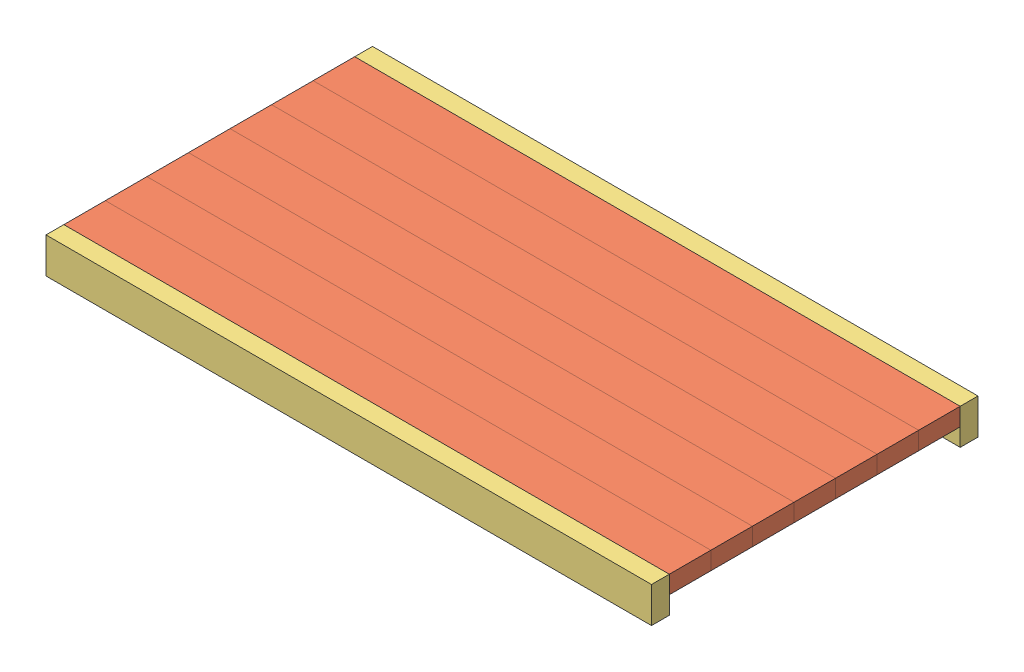
SolidWorks assembly lid, configuration Default. Lengths in mm.
Overall size (1295.4 76.2 698.5).
11 component instances, 3 part files, 8 mates.
Components (placement in the parent):
- plywood_lid-1: plywood_lid [Default] at (50.5401 17.8556 -38.8001) size (1219.2 6.35 622.3)
- long_side-1: long_side [Default] at (-16.1318 62.0613 -12.0499) size (1295.4 38.1 622.3)
  - 51in_2x4-1: 51in_2x4 [Default] at (-580.1032 -18.8057 235.4979) x (0 0 -1) z (1 0 0) size (88.9 38.1 1295.4)
  - 51in_2x4-2: 51in_2x4 [Default] at (-580.1032 -18.8057 146.5979) x (0 0 -1) z (1 0 0) size (88.9 38.1 1295.4)
  - 51in_2x4-3: 51in_2x4 [Default] at (715.2968 -18.8057 -297.9021) x (0 0 1) z (-1 0 0) size (88.9 38.1 1295.4)
  - 51in_2x4-4: 51in_2x4 [Default] at (715.2968 -18.8057 57.6979) x (0 0 1) z (-1 0 0) size (88.9 38.1 1295.4)
  - 51in_2x4-5: 51in_2x4 [Default] at (715.2968 -18.8057 -31.2021) x (0 0 1) z (-1 0 0) size (88.9 38.1 1295.4)
  - 51in_2x4-6: 51in_2x4 [Default] at (715.2968 -18.8057 -120.1021) x (0 0 1) z (-1 0 0) size (88.9 38.1 1295.4)
  - 51in_2x4-7: 51in_2x4 [Default] at (715.2968 -18.8057 -209.0021) x (0 0 1) z (-1 0 0) size (88.9 38.1 1295.4)
- 51in_3in_1-5in-1: 51in_3in_1-5in [Default] at (-596.235 24.2056 -373.452) x (0 1 0) z (1 0 0) size (76.2 38.1 1295.4)
- 51in_3in_1-5in-2: 51in_3in_1-5in [Default] at (-596.235 24.2056 286.948) x (0 -1 0) z (1 0 0) size (76.2 38.1 1295.4)
Mates (geometry in assembly coordinates):
- Coincident1: coincident anti-aligned: plane of plywood_lid-1 through (660.1401 24.2056 272.3499) normal (0 1 0); plane of long_side-1/51in_2x4-7 through (-596.235 24.2056 -265.502) normal (0 -1 0)
- Parallel1: parallel aligned: plane of plywood_lid-1 through (660.1401 24.2056 -349.9501) normal (1 0 0); plane of long_side-1/51in_2x4-5 through (699.165 24.2056 1.198) normal (1 0 0)
- Coincident9: coincident aligned: plane of long_side-1/51in_2x4-3 through (-596.235 62.3056 -354.402) normal (0 1 0); plane of 51in_3in_1-5in-1 through (699.165 62.3056 -354.402) normal (0 1 0)
- Coincident10: coincident aligned: plane of long_side-1/51in_2x4-3 through (699.165 24.2056 -265.502) normal (1 0 0); plane of 51in_3in_1-5in-1 through (699.165 62.3056 -392.502) normal (1 0 0)
- Coincident11: coincident anti-aligned: plane of long_side-1/51in_2x4-3 through (-596.235 62.3056 -354.402) normal (0 0 -1); plane of 51in_3in_1-5in-1 through (699.165 -13.8944 -354.402) normal (0 0 1)
- Coincident12: coincident anti-aligned: plane of long_side-1/51in_2x4-1 through (699.165 62.3056 267.898) normal (0 0 1); plane of 51in_3in_1-5in-2 through (699.165 62.3056 267.898) normal (0 0 -1)
- Coincident13: coincident aligned: plane of long_side-1/51in_2x4-1 through (699.165 62.3056 267.898) normal (0 1 0); plane of 51in_3in_1-5in-2 through (699.165 62.3056 267.898) normal (0 1 0)
- Coincident14: coincident aligned: plane of long_side-1/51in_2x4-5 through (-596.235 24.2056 1.198) normal (-1 0 0); plane of 51in_3in_1-5in-2 through (-596.235 -13.8944 305.998) normal (-1 0 0)
